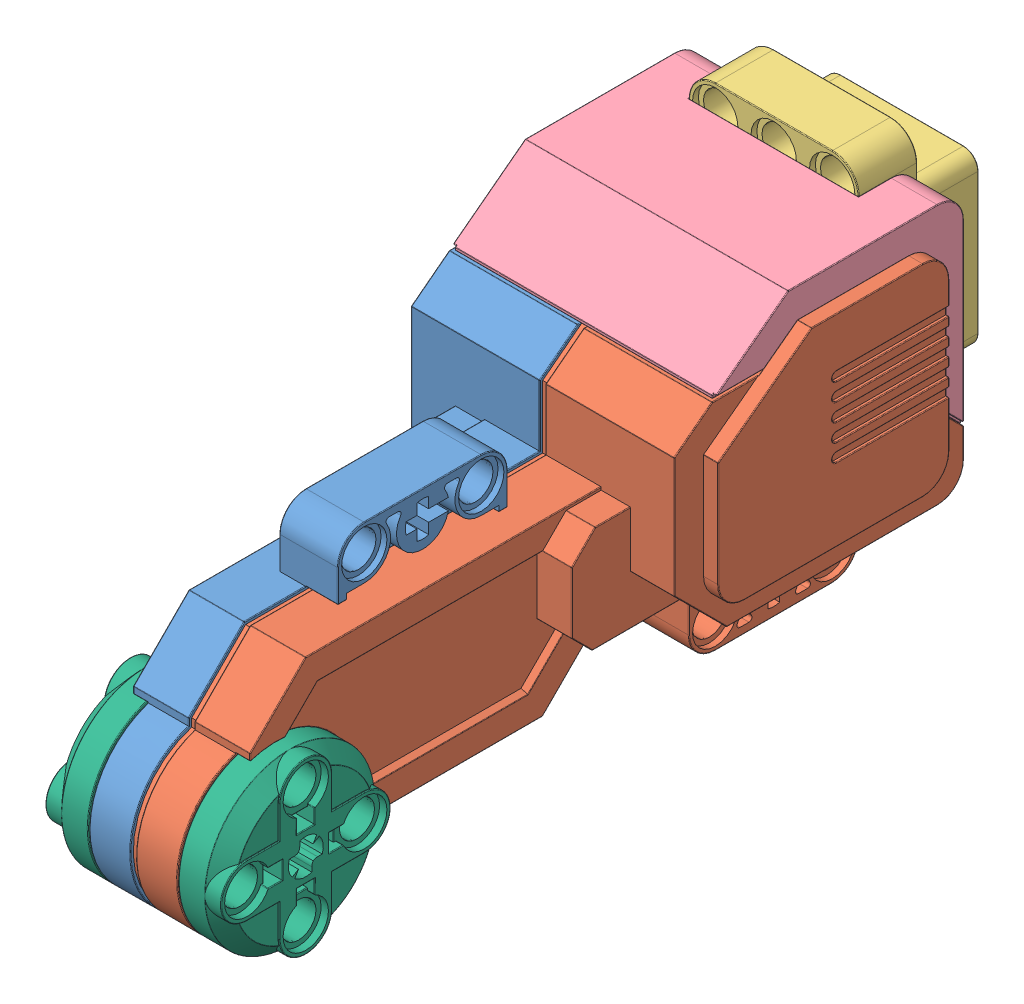
SolidWorks assembly EV3 Large Servo Motor, configuration Default. Lengths in mm.
Overall size (40 55.2 107.2).
9 component instances, 6 part files, 0 mates.
Components (placement in the parent):
- 95658.stp-1: 95658.stp [Default] at origin size (40 55.2 107.2)
  - 99550c01.stp-1: 99550c01.stp [Default] at origin size (40 55.2 107.2)
    - 99550-LtBluishGray.stp-1: 99550-LtBluishGray.stp [Default] x (-1 0 0) z (0 0 -1) size (24 47.6 95.62)
    - 99551-LtBluishGray.stp-1: 99551-LtBluishGray.stp [Default] at (0.8 0 0) x (-1 0 0) z (0 0 -1) size (20.4 47.6 95.61)
    - 10825-LtBluishGray.stp-1: 10825-LtBluishGray.stp [Default] at (0.4 24 -84) x (-1 0 0) z (0 0 -1) size (30.4 39.2 19.6)
    - 99555-White.stp-1: 99555-White.stp [Default] at (0.4 24.2 -70.2) x (-1 0 0) z (0 0 -1) size (36 27.86 34)
    - 54732b-LtBluishGray.stp-1: 54732b-LtBluishGray.stp [Default] at (0.4 23.6 -95.6) x (-1 0 0) z (0 0 -1) size (12 14.56 14.4)
  - 99617-Red.stp-1: 99617-Red.stp [Default] at (-5.8 0 0) x (-1 0 0) z (0 0 -1) size (12 23.2 23.2)
  - 99617-Red.stp-2: 99617-Red.stp [Default] at (6.6 0 0) size (12 23.2 23.2)
